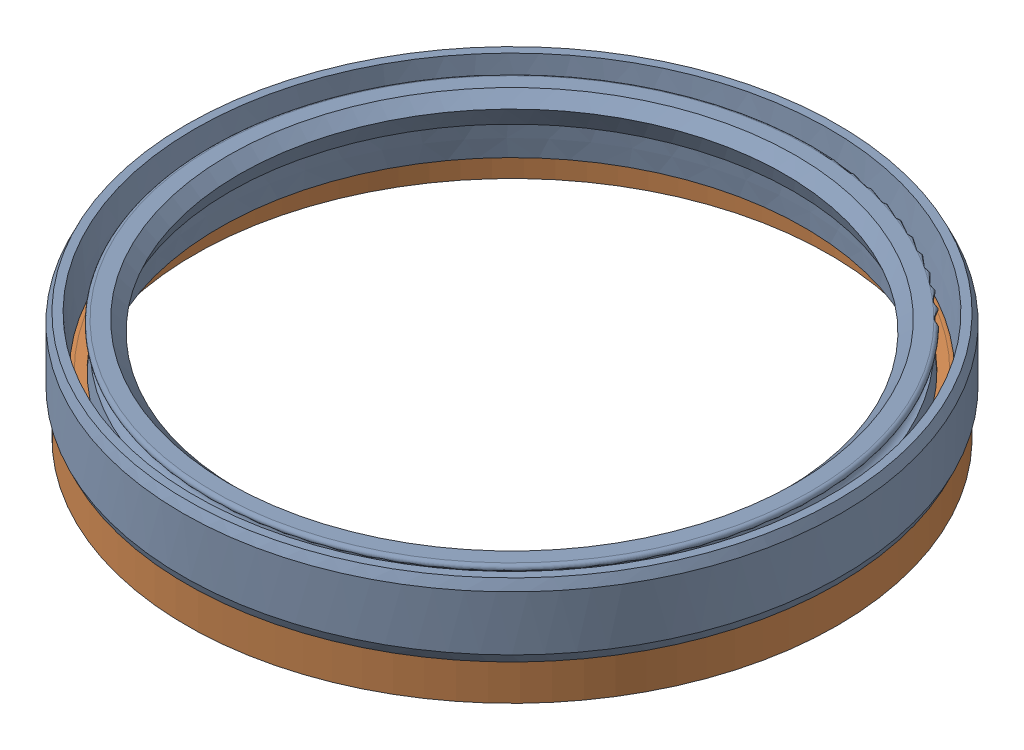
SolidWorks assembly b90x110x12_gb9877_1_2, configuration 默认. Lengths in mm.
Overall size (108.6 17.9 108.6).
2 component instances, 2 part files, 0 mates.
Components (placement in the parent):
- b90x110x12_gb9877_1_rubber_2-1: b90x110x12_gb9877_1_rubber_2 [默认] at origin size (108.6 12 108.6)
- b90x110x12_gb9877_1_frame_2-1: b90x110x12_gb9877_1_frame_2 [默认] at (0 -2.4 0) x (-1 0 0) z (0 0 1) size (107.2 9.5 107.2)
